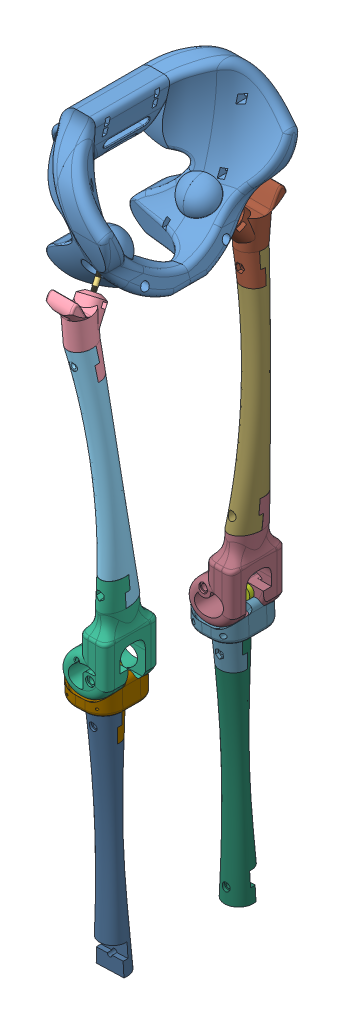
SolidWorks assembly 09_BipedalRobot_Assembly, configuration Default. Lengths in mm.
19 component instances, 15 part files, 49 mates.
Components (placement in the parent):
- 02_01_Pelvis-1: 02_01_Pelvis [Default] at origin size (197.88 220.17 282.18)
- 6630T310_METRIC BLACK POLYPROPYLENE BALL KNOB-1: 6630T310_METRIC BLACK POLYPROPYLENE BALL KNOB [6630T31] at (-58.671 -58.8069 72.4936) x (0.804974 0.48308 0.344458) z (-0.194905 0.763657 -0.6155) size (38 38 37.9)
- 92997A108_CORROSION-RESISTANT SETUP STUD-1: 92997A108_CORROSION-RESISTANT SETUP STUD [92997A108] at (-55.0653 -72.9345 83.8804) x (0.017759 0.630179 0.776247) z (0.194905 -0.763657 0.6155) size (6.34 6.15 50.8)
- 03_02_FemurHead_Right-1: 03_02_FemurHead_Right [Default] at (-45.3395 -121.5667 106.123) x (1 0 0) z (0 -0.087156 0.996195) size (46.92 105.86 63.35)
- 03_01_FemurBone_Right-1: 03_01_FemurBone_Right [Default] at (-44.1058 -425.8587 87.0078) x (1 0 0) z (0 -0.087156 0.996195) size (54.81 304.92 60)
- 04_01_KneeTop_Right-1: 04_01_KneeTop_Right [Default] at (-35.6321 -504.5163 84.7583) size (77.56 157.24 74.14)
- 04_05_BackLink-1: 04_05_BackLink [Default] at (-42.5577 -521.5571 84.8583) x (0.712112 0.702066 0) z (0 0 1) size (62.75 16 5.9)
- 04_06_FrontLink-1: 04_06_FrontLink [Default] at (-31.6099 -512.6089 78.7583) x (0.469804 -0.882771 0) z (0 0 1) size (67.43 16 3.9)
- 04_02_KneeBottom_Right-1: 04_02_KneeBottom_Right [Default] at (-43.0474 -546.2764 84.7583) x (0.999391 0.034899 0) z (0 0 1) size (78.49 85.12 75.75)
- 05_01_Tibial_Right-1: 05_01_Tibial_Right [Default] at (-42.6984 -556.2703 84.7583) x (0.999391 0.034899 0) z (0 0 1) size (38.19 305.23 41.5)
- 6630T310_METRIC BLACK POLYPROPYLENE BALL KNOB-2: 6630T310_METRIC BLACK POLYPROPYLENE BALL KNOB [6630T31] at (-58.671 -58.8069 -72.4936) x (0.963134 0.030376 0.2673) z (-0.194905 0.763657 0.6155) size (38 38 37.9)
- 92997A108_CORROSION-RESISTANT SETUP STUD-2: 92997A108_CORROSION-RESISTANT SETUP STUD [92997A108] at (-55.0653 -72.9345 -83.8804) x (-0.54916 -0.604916 0.576628) z (-0.194905 0.763657 0.6155) size (6.34 6.15 50.8)
- 03_04_FemurHead_Left-1: 03_04_FemurHead_Left [Default] at (-45.3395 -121.5667 -106.123) x (1 0 0) z (0 0.087156 0.996195) size (46.92 105.86 63.35)
- 03_03_FemurBone_Left-1: 03_03_FemurBone_Left [Default] at (-44.1058 -425.8587 -87.0078) x (1 0 0) z (0 0.087156 0.996195) size (54.81 304.92 60)
- 04_03_KneeTop_Left-1: 04_03_KneeTop_Left [Default] at (-35.6321 -504.5163 -84.7583) size (77.56 157.24 74.14)
- 04_05_BackLink-2: 04_05_BackLink [Default] at (-42.5577 -521.5571 -90.7583) x (0.712112 0.702066 0) z (0 0 1) size (62.75 16 5.9)
- 04_06_FrontLink-2: 04_06_FrontLink [Default] at (-31.6099 -512.6089 -84.6583) x (-0.469804 0.882771 0) z (0 0 1) size (67.43 16 3.9)
- 04_04_KneeBottom_Left-1: 04_04_KneeBottom_Left [Default] at (-43.0474 -546.2764 -84.8583) x (0.999391 0.034899 0) z (0 0 1) size (78.49 85.12 75.75)
- 05_02_Tibial_Left-1: 05_02_Tibial_Left [Default] at (-42.6984 -556.2703 -84.8583) x (0.999391 0.034899 0) z (0 0 1) size (38.19 304.9 38.19)
Mates (geometry in assembly coordinates):
- Concentric1: concentric: sphere of 02_01_Pelvis-1; sphere of 6630T310_METRIC BLACK POLYPROPYLENE BALL KNOB-1
- Concentric2: concentric aligned: circle of 6630T310_METRIC BLACK POLYPROPYLENE BALL KNOB-1; cylinder of 92997A108_CORROSION-RESISTANT SETUP STUD-1 through (-50.1927 -92.0259 99.2679) axis (0.194905 -0.763657 0.6155) radius 3.02
- Coincident1: coincident anti-aligned: plane of 6630T310_METRIC BLACK POLYPROPYLENE BALL KNOB-1 through (-59.9379 -53.8431 68.4929) normal (0.194905 -0.763657 0.6155); plane of 92997A108_CORROSION-RESISTANT SETUP STUD-1 through (-59.9379 -53.8431 68.4929) normal (-0.194905 0.763657 -0.6155)
- Concentric3: concentric anti-aligned: cylinder of 92997A108_CORROSION-RESISTANT SETUP STUD-1 through (-50.1927 -92.0259 99.2679) axis (0.194905 -0.763657 0.6155) radius 3.02; cylinder of 03_02_FemurHead_Right-1 through (-50.1927 -92.0259 99.2679) axis (-0.194905 0.763657 -0.6155) radius 3.125
- Coincident2: coincident anti-aligned: plane of 92997A108_CORROSION-RESISTANT SETUP STUD-1 through (-50.1927 -92.0259 99.2679) normal (0.194905 -0.763657 0.6155); plane of 03_02_FemurHead_Right-1 through (-50.1927 -92.0259 99.2679) normal (-0.194905 0.763657 -0.6155)
- Coincident3: coincident anti-aligned: plane of 03_02_FemurHead_Right-1 through (-6.4724 -121.8919 109.8397) normal (0 -0.087156 0.996195); plane of 03_01_FemurBone_Right-1 through (-6.4656 -425.532 83.2746) normal (0 0.087156 -0.996195)
- Coincident4: coincident anti-aligned: plane of 03_02_FemurHead_Right-1 through (-45.3395 -122.2223 113.6156) normal (0 -0.996195 -0.087156); plane of 03_01_FemurBone_Right-1 through (-45.3394 -122.2223 113.6157) normal (0 0.996195 0.087156)
- Concentric4: concentric aligned: cylinder of 03_02_FemurHead_Right-1 through (-41.8015 -143.6299 139.7315) axis (0 0.087156 -0.996195) radius 3.175; cylinder of 03_01_FemurBone_Right-1 through (-41.8015 -143.4149 137.2744) axis (0 0.087156 -0.996195) radius 3.175
- Coincident5: coincident anti-aligned: plane of 03_01_FemurBone_Right-1 through (-6.4656 -425.6763 84.9233) normal (0 -0.087156 0.996195); plane of 04_01_KneeTop_Right-1 through (-0.2749 -503.9317 78.0769) normal (0 0.087156 -0.996195)
- Coincident6: coincident anti-aligned: plane of 03_01_FemurBone_Right-1 through (-6.4656 -387.9074 90.3712) normal (0 -0.996195 -0.087156); plane of 04_01_KneeTop_Right-1 through (-0.2749 -388.3058 94.9254) normal (0 0.996195 0.087156)
- Concentric5: concentric anti-aligned: cylinder of 03_01_FemurBone_Right-1 through (-23.6321 -409.1 114.0299) axis (0 0.087156 -0.996195) radius 3.175; cylinder of 04_01_KneeTop_Right-1 through (-23.6321 -403.1666 46.2101) axis (0 -0.087156 0.996195) radius 3.25
- Concentric6: concentric aligned: cylinder of 04_01_KneeTop_Right-1 through (-25.9121 -505.1463 121.7583) axis (0 0 -1) radius 3; cylinder of 04_05_BackLink-1 through (-25.9121 -505.1463 90.7583) axis (0 0 -1) radius 3.15
- Coincident7: coincident anti-aligned: plane of 04_01_KneeTop_Right-1 through (-67.8349 -532.8861 90.7583) normal (0 0 -1); plane of 04_05_BackLink-1 through (-25.9121 -505.1463 90.7583) normal (0 0 1)
- Concentric7: concentric anti-aligned: cylinder of 04_01_KneeTop_Right-1 through (-43.6921 -489.9063 47.7583) axis (0 0 1) radius 3; cylinder of 04_06_FrontLink-1 through (-43.6921 -489.9063 84.6583) axis (0 0 -1) radius 3.15
- Coincident8: coincident anti-aligned: plane of 04_01_KneeTop_Right-1 through (-67.8349 -532.8861 78.7583) normal (0 0 1); plane of 04_06_FrontLink-1 through (-19.5277 -535.3116 78.7583) normal (0 0 -1)
- Concentric8: concentric anti-aligned: cylinder of 04_05_BackLink-1 through (-59.2033 -537.9679 90.7583) axis (0 0 -1) radius 3.15; cylinder of 04_02_KneeBottom_Right-1 through (-59.2033 -537.9679 69.7583) axis (0 0 1) radius 3.1
- Coincident9: coincident anti-aligned: plane of 04_05_BackLink-1 through (-25.9121 -505.1463 90.7583) normal (0 0 1); plane of 04_02_KneeBottom_Right-1 through (-34.8274 -504.104 90.7583) normal (0 0 -1)
- Concentric9: concentric anti-aligned: cylinder of 04_06_FrontLink-1 through (-19.5277 -535.3116 84.6583) axis (0 0 -1) radius 3.15; cylinder of 04_02_KneeBottom_Right-1 through (-19.5277 -535.3116 69.7583) axis (0 0 1) radius 3.1
- LimitAngle1: limit planar angle = 0.034907 rad aligned: plane of 04_02_KneeBottom_Right-1 through (-7.9656 -505.0269 122.2583) normal (0.999391 0.034899 0); plane of 04_01_KneeTop_Right-1 through (-5.6321 -455.7765 121.7583) normal (1 0 0)
- Coincident11: coincident anti-aligned: plane of 04_02_KneeBottom_Right-1 through (-82.9466 -547.6697 80.8456) normal (0 0 1); plane of 05_01_Tibial_Right-1 through (-61.7832 -556.9367 80.8456) normal (0 0 -1)
- Coincident12: coincident anti-aligned: plane of 04_02_KneeBottom_Right-1; plane of 05_01_Tibial_Right-1
- Concentric10: concentric aligned: cylinder of 04_02_KneeBottom_Right-1 through (-41.8513 -575.3023 46.8849) axis (0 0 1) radius 3.25; cylinder of 05_01_Tibial_Right-1 through (-41.8513 -575.3023 65.6619) axis (0 0 1) radius 3.25
- Concentric11: concentric: sphere of 02_01_Pelvis-1; sphere of 6630T310_METRIC BLACK POLYPROPYLENE BALL KNOB-2
- Concentric12: concentric anti-aligned: circle of 6630T310_METRIC BLACK POLYPROPYLENE BALL KNOB-2; cylinder of 92997A108_CORROSION-RESISTANT SETUP STUD-2 through (-59.9379 -53.8431 -68.4929) axis (-0.194905 0.763657 0.6155) radius 3.02
- Coincident13: coincident anti-aligned: plane of 6630T310_METRIC BLACK POLYPROPYLENE BALL KNOB-2 through (-59.9379 -53.8431 -68.4929) normal (0.194905 -0.763657 -0.6155); plane of 92997A108_CORROSION-RESISTANT SETUP STUD-2 through (-59.9379 -53.8431 -68.4929) normal (-0.194905 0.763657 0.6155)
- Concentric13: concentric aligned: cylinder of 92997A108_CORROSION-RESISTANT SETUP STUD-2 through (-59.9379 -53.8431 -68.4929) axis (-0.194905 0.763657 0.6155) radius 3.02; cylinder of 03_04_FemurHead_Left-1 through (-50.1927 -92.0259 -99.2679) axis (-0.194905 0.763657 0.6155) radius 3.125
- Coincident14: coincident anti-aligned: plane of 92997A108_CORROSION-RESISTANT SETUP STUD-2 through (-50.1927 -92.0259 -99.2679) normal (0.194905 -0.763657 -0.6155); plane of 03_04_FemurHead_Left-1 through (-50.1927 -92.0259 -99.2679) normal (-0.194905 0.763657 0.6155)
- Coincident15: coincident anti-aligned: plane of 03_04_FemurHead_Left-1 through (-6.4724 -121.8919 -109.8397) normal (0 -0.087156 -0.996195); plane of 03_03_FemurBone_Left-1 through (-6.4656 -425.532 -83.2746) normal (0 0.087156 0.996195)
- Coincident16: coincident anti-aligned: plane of 03_04_FemurHead_Left-1 through (-45.3395 -122.2223 -113.6156) normal (0 -0.996195 0.087156); plane of 03_03_FemurBone_Left-1 through (-45.3394 -122.2223 -113.6157) normal (0 0.996195 -0.087156)
- Concentric14: concentric aligned: cylinder of 03_04_FemurHead_Left-1 through (-41.8015 -143.6299 -139.7315) axis (0 0.087156 0.996195) radius 3.175; cylinder of 03_03_FemurBone_Left-1 through (-41.8015 -143.4149 -137.2744) axis (0 0.087156 0.996195) radius 3.175
- Coincident17: coincident anti-aligned: plane of 03_03_FemurBone_Left-1 through (-6.4656 -425.6763 -84.9233) normal (0 -0.087156 -0.996195); plane of 04_03_KneeTop_Left-1 through (-0.2749 -503.9317 -78.0769) normal (0 0.087156 0.996195)
- Coincident18: coincident anti-aligned: plane of 03_03_FemurBone_Left-1 through (-6.4656 -387.9074 -90.3712) normal (0 -0.996195 0.087156); plane of 04_03_KneeTop_Left-1 through (-0.2749 -388.3058 -94.9254) normal (0 0.996195 -0.087156)
- Concentric15: concentric anti-aligned: cylinder of 03_03_FemurBone_Left-1 through (-23.6321 -409.1 -114.0299) axis (0 0.087156 0.996195) radius 3.175; cylinder of 04_03_KneeTop_Left-1 through (-23.6321 -403.1666 -46.2101) axis (0 -0.087156 -0.996195) radius 3.25
- Concentric16: concentric anti-aligned: cylinder of 04_03_KneeTop_Left-1 through (-25.9121 -505.1463 -121.7583) axis (0 0 1) radius 3; cylinder of 04_05_BackLink-2 through (-25.9121 -505.1463 -84.8583) axis (0 0 -1) radius 3.15
- Coincident19: coincident anti-aligned: plane of 04_03_KneeTop_Left-1 through (-67.8349 -532.8861 -90.7583) normal (0 0 1); plane of 04_05_BackLink-2 through (-25.9121 -505.1463 -90.7583) normal (0 0 -1)
- Concentric17: concentric aligned: cylinder of 04_03_KneeTop_Left-1 through (-43.6921 -489.9063 -47.7583) axis (0 0 -1) radius 3; cylinder of 04_06_FrontLink-2 through (-43.6921 -489.9063 -78.7583) axis (0 0 -1) radius 3.15
- Coincident20: coincident anti-aligned: plane of 04_03_KneeTop_Left-1 through (-67.8349 -532.8861 -78.7583) normal (0 0 -1); plane of 04_06_FrontLink-2 through (-43.6921 -489.9063 -78.7583) normal (0 0 1)
- Concentric18: concentric aligned: cylinder of 04_05_BackLink-2 through (-59.2033 -537.9679 -84.8583) axis (0 0 -1) radius 3.15; cylinder of 04_04_KneeBottom_Left-1 through (-59.2033 -537.9679 -46.9849) axis (0 0 -1) radius 3.2
- Coincident21: coincident anti-aligned: plane of 04_05_BackLink-2 through (-25.9121 -505.1463 -84.8583) normal (0 0 1); plane of 04_04_KneeBottom_Left-1 through (-59.2033 -537.9679 -84.8583) normal (0 0 -1)
- Concentric19: concentric aligned: cylinder of 04_06_FrontLink-2 through (-19.5277 -535.3116 -78.7583) axis (0 0 -1) radius 3.15; cylinder of 04_04_KneeBottom_Left-1 through (-19.5277 -535.3116 -46.9849) axis (0 0 -1) radius 3.2
- LimitAngle2: limit planar angle = 0.034907 rad aligned: plane of 04_03_KneeTop_Left-1 through (-5.6321 -455.7765 -121.7583) normal (1 0 0); plane of 04_04_KneeBottom_Left-1 through (-7.9656 -505.0269 -122.3583) normal (0.999391 0.034899 0)
- Coincident23: coincident anti-aligned: plane of 04_04_KneeBottom_Left-1 through (-82.9466 -547.6697 -80.9456) normal (0 0 -1); plane of 05_02_Tibial_Left-1 through (-61.7832 -556.9367 -80.9456) normal (0 0 1)
- Coincident24: coincident anti-aligned: plane of 04_04_KneeBottom_Left-1 through (-82.5976 -557.6636 -84.8583) normal (0.034899 -0.999391 0); plane of 05_02_Tibial_Left-1 through (-42.6984 -556.2703 -84.8583) normal (-0.034899 0.999391 0)
- Concentric20: concentric aligned: cylinder of 04_04_KneeBottom_Left-1 through (-41.8513 -575.3023 -46.9849) axis (0 0 -1) radius 3.25; cylinder of 05_02_Tibial_Left-1 through (-41.8513 -575.3023 -65.7619) axis (0 0 -1) radius 3.25
- Parallel6: parallel: plane of assembly through (0 0 0) normal (1 0 0); plane of assembly; plane of 04_01_KneeTop_Right-1 through (-5.6321 -455.7765 121.7583) normal (1 0 0)
- Parallel7: parallel: plane of assembly through (0 0 0) normal (1 0 0); plane of assembly; plane of 04_03_KneeTop_Left-1 through (-5.6321 -455.7765 -121.7583) normal (1 0 0)
- Parallel8: parallel aligned: 
- Parallel9: parallel: plane of assembly through (0 0 0) normal (0 0 1); plane of assembly; plane of 04_01_KneeTop_Right-1 through (-35.6321 -504.5163 47.7583) normal (0 0 -1)
- Parallel10: parallel: plane of assembly through (0 0 0) normal (0 0 1); plane of assembly; plane of 04_03_KneeTop_Left-1 through (-35.6321 -504.5163 -47.7583) normal (0 0 1)
